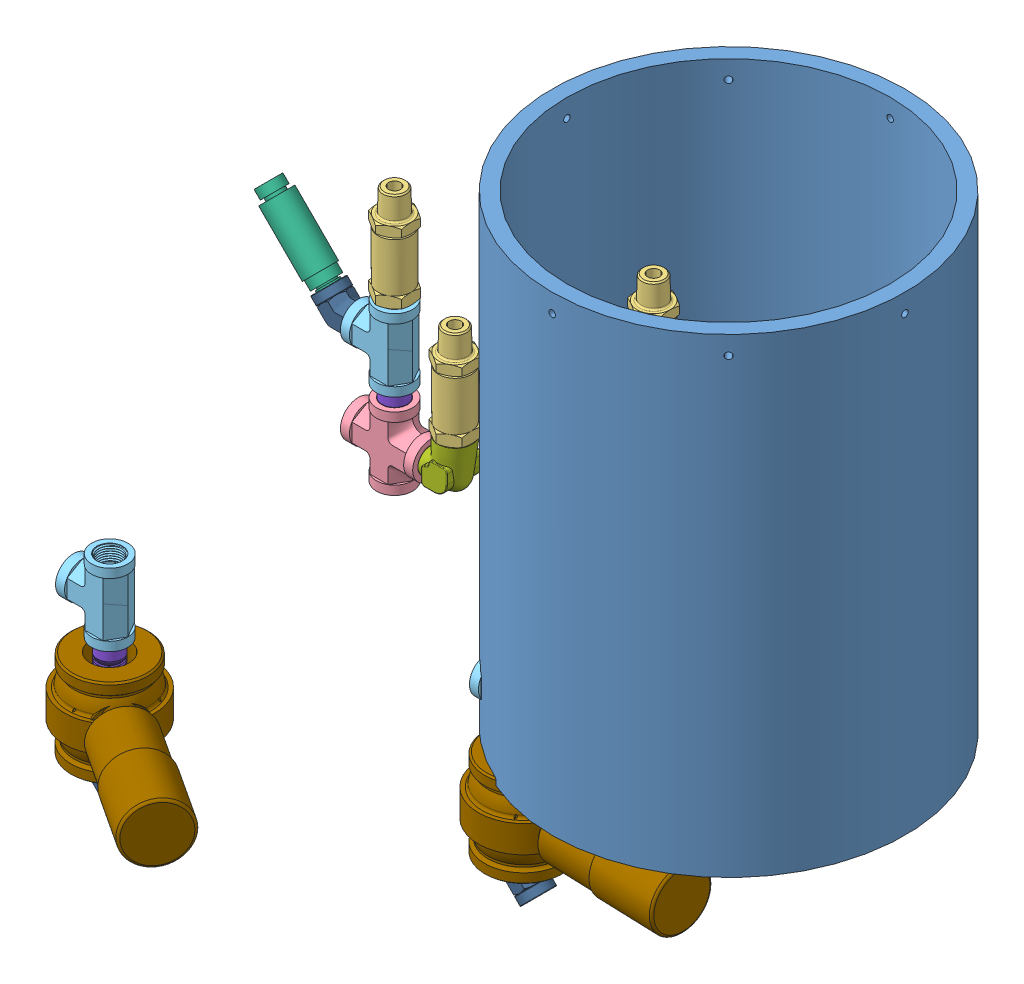
SolidWorks assembly FinCanAssembly, configuration Default. Lengths in mm.
Overall size (594.72 511.85 548.05).
27 component instances, 10 part files, 43 mates.
Components (placement in the parent):
- 000070-R03_FIN_CAN_AF-1: 000070-R03_FIN_CAN_AF [Default] at (23.1188 -196.0045 -17.088) size (304.8 406.4 304.8)
- launch_rail_lugs-1: launch_rail_lugs [Default] at (-92.4476 -84.8795 -132.6545) x (-0.707107 0 0.707107) z (-0.707107 0 -0.707107) size (76.2 32.2 34.22)
- TIN20021-1: TIN20021 [Default] at (7.6331 145.2519 32.2173) x (0 -1 0) z (0 0 1) size (102.11 28.58 33)
- TIN20021-2: TIN20021 [Default] at (-301.1748 13.7827 -52.7696) x (0 -1 0) z (0 0 1) size (102.11 28.58 33)
- 51205K175_EXTREME-PRESSURE 316 SS THREADED PIPE FITTING-1: 51205K175_EXTREME-PRESSURE 316 SS THREADED PIPE FITTING [51205K175] at (7.6331 -24.0899 32.2173) size (63.86 63.86 31.16)
- 51205K175_EXTREME-PRESSURE 316 SS THREADED PIPE FITTING-2: 51205K175_EXTREME-PRESSURE 316 SS THREADED PIPE FITTING [51205K175] at (-301.1748 -155.5591 -52.7696) x (0 -1 0) z (0 0 1) size (63.86 63.86 31.16)
- TIN20021-3: TIN20021 [Default] at (-248.9047 -63.8175 -52.7696) x (0 -1 0) z (0 0 1) size (102.11 28.58 33)
- TIN20021-6: TIN20021 [Default] at (59.9031 67.6517 32.2173) x (0 -1 0) z (0 0 1) size (102.11 28.58 33)
- 51205K245_EXTREME-PRESSURE 316 SS THREADED PIPE FITTING-1: 51205K245_EXTREME-PRESSURE 316 SS THREADED PIPE FITTING [51205K245] at (-301.1748 -81.9753 -52.7696) x (0 1 0) z (0 0 1) size (63.86 47.51 31.16)
- cryo-pducer-temp-1: cryo-pducer-temp [Default] at (-350.8641 -76.2279 -52.7696) x (0.707107 0.707107 0) z (0 0 1) size (25.65 83.82 25.65)
- 51205K245_EXTREME-PRESSURE 316 SS THREADED PIPE FITTING-2: 51205K245_EXTREME-PRESSURE 316 SS THREADED PIPE FITTING [51205K245] at (7.6331 49.4939 32.2173) x (0 1 0) z (0 0 1) size (63.86 47.51 31.16)
- cryo-pducer-temp-2: cryo-pducer-temp [Default] at (-13.4489 49.4939 32.2173) x (0 1 0) z (0 0 1) size (25.65 83.82 25.65)
- 3861T240_MED-PRESSURE ANODIZED ALUM THRD PIPE FITTING-1: 3861T240_MED-PRESSURE ANODIZED ALUM THRD PIPE FITTING [3861T24] at (-248.9047 -125.7935 -52.7696) x (0 0 -1) z (0 1 0) size (30.97 56.51 41.63)
- 44665K173_STANDARD-WALL ALUMINUM THREADED PIPE NIPPLE-1: 44665K173_STANDARD-WALL ALUMINUM THREADED PIPE NIPPLE [44665K173] at (-301.1748 -118.7672 -52.7696) x (1 0 0) z (0 -1 0) size (22.19 22.36 51.97)
- 44665K173_STANDARD-WALL ALUMINUM THREADED PIPE NIPPLE-2: 44665K173_STANDARD-WALL ALUMINUM THREADED PIPE NIPPLE [44665K173] at (7.6331 12.702 32.2173) x (1 0 0) z (0 -1 0) size (22.19 22.36 51.97)
- 3861T240_MED-PRESSURE ANODIZED ALUM THRD PIPE FITTING-2: 3861T240_MED-PRESSURE ANODIZED ALUM THRD PIPE FITTING [3861T24] at (59.9031 5.6757 32.2173) x (0 0 -1) z (0 1 0) size (30.97 56.51 41.63)
- atomatik-1: atomatik [Default] at (58.6758 -183.8479 -36.0375) size (76.23 180.98 78)
- atomatik-2: atomatik [Default] at (-229.8589 -151.0153 264.6801) x (0 -1 0) z (-0.546944 0 0.837169) size (76.23 180.98 78)
- atomatik-3: atomatik [Default] at (-46.8177 -221.3586 90.098) x (0 -1 0) z (-0.035722 0 0.999362) size (76.23 180.98 78)
- atomatik-4: atomatik [Default] at (57.6992 -182.5795 58.8478) size (76.23 180.98 78)
- 51205K245_EXTREME-PRESSURE 316 SS THREADED PIPE FITTING-3: 51205K245_EXTREME-PRESSURE 316 SS THREADED PIPE FITTING [51205K245] at (-46.8177 -148.3929 90.098) x (0 1 0) z (0 0 1) size (63.86 47.51 31.16)
- 44665K173_STANDARD-WALL ALUMINUM THREADED PIPE NIPPLE-3: 44665K173_STANDARD-WALL ALUMINUM THREADED PIPE NIPPLE [44665K173] at (-46.8177 -185.1848 90.098) x (1 0 0) z (0 -1 0) size (22.19 22.36 51.97)
- 51205K245_EXTREME-PRESSURE 316 SS THREADED PIPE FITTING-4: 51205K245_EXTREME-PRESSURE 316 SS THREADED PIPE FITTING [51205K245] at (-229.8589 -78.0496 264.6801) x (0 1 0) z (0 0 1) size (63.86 47.51 31.16)
- 44665K173_STANDARD-WALL ALUMINUM THREADED PIPE NIPPLE-4: 44665K173_STANDARD-WALL ALUMINUM THREADED PIPE NIPPLE [44665K173] at (-229.8589 -114.8415 264.6801) x (1 0 0) z (0 -1 0) size (22.19 22.36 51.97)
- 48805K184_PRECISION EXTREME-PRESSURE 316SS PIPE FITTING-1: 48805K184_PRECISION EXTREME-PRESSURE 316SS PIPE FITTING [48805K184] at (-46.8177 -279.661 90.098) x (0 -1 0) z (0 0 1) size (48.72 34.63 25.66)
- 48805K184_PRECISION EXTREME-PRESSURE 316SS PIPE FITTING-2: 48805K184_PRECISION EXTREME-PRESSURE 316SS PIPE FITTING [48805K184] at (-229.8589 -209.3177 264.6801) x (0 -1 0) z (0 0 1) size (48.72 34.63 25.66)
- 48805K184_PRECISION EXTREME-PRESSURE 316SS PIPE FITTING-3: 48805K184_PRECISION EXTREME-PRESSURE 316SS PIPE FITTING [48805K184] at (-345.1168 -81.9753 -52.7696) x (-1 0 0) z (0 0 -1) size (48.72 34.63 25.66)
Mates (geometry in assembly coordinates):
- Concentric1: concentric aligned: cylinder of 000070-R03_FIN_CAN_AF-1 through (23.1188 210.3955 -17.088) axis (0 -1 0) radius 152.4; cylinder of launch_rail_lugs-1 through (23.1188 -53.1295 -17.088) axis (0 -1 0) radius 152.4
- Concentric2: concentric aligned: cylinder of 000070-R03_FIN_CAN_AF-1 through (-90.7059 -69.0045 -118.7894) axis (-0.707107 0 -0.707107) radius 1.7272; cylinder of launch_rail_lugs-1 through (-98.5093 -69.0045 -126.5928) axis (-0.707107 0 -0.707107) radius 2.4574
- Distance8: distance = 2.54 mm anti-aligned: plane of 51205K245_EXTREME-PRESSURE 316 SS THREADED PIPE FITTING-1 through (-301.1748 -50.7333 -52.7696) normal (0 1 0); plane of TIN20021-2 through (-301.1748 -48.1933 -61.0184) normal (0 -1 0)
- Concentric19: concentric aligned: cone of TIN20021-1 through (7.6331 81.8471 32.2173) axis (0 -1 0); cylinder of 51205K245_EXTREME-PRESSURE 316 SS THREADED PIPE FITTING-2 through (7.6331 67.2739 32.2173) axis (0 -1 0) radius 8.001
- Distance11: distance = 2.54 mm anti-aligned: plane of TIN20021-1 through (7.6331 83.2759 23.9684) normal (0 -1 0); plane of 51205K245_EXTREME-PRESSURE 316 SS THREADED PIPE FITTING-2 through (7.6331 80.7359 32.2173) normal (0 1 0)
- Concentric21: concentric aligned: cylinder of 51205K245_EXTREME-PRESSURE 316 SS THREADED PIPE FITTING-2 through (-10.1469 49.4939 32.2173) axis (1 0 0) radius 8.001; cylinder of cryo-pducer-temp-2 through (-13.4489 49.4939 32.2173) axis (1 0 0) radius 8.89
- Distance12: distance = 2.54 mm anti-aligned: plane of cryo-pducer-temp-2 through (-26.1489 60.9239 32.2173) normal (1 0 0); plane of 51205K245_EXTREME-PRESSURE 316 SS THREADED PIPE FITTING-2 through (-23.6089 49.4939 32.2173) normal (-1 0 0)
- Concentric22: concentric anti-aligned: cylinder of 51205K175_EXTREME-PRESSURE 316 SS THREADED PIPE FITTING-2 through (-301.1748 -173.3391 -52.7696) axis (0 1 0) radius 8.001; cylinder of 44665K173_STANDARD-WALL ALUMINUM THREADED PIPE NIPPLE-1 through (-301.1748 -92.78 -52.7696) axis (0 -1 0) radius 7.8994
- Coincident14: coincident aligned: plane of 51205K175_EXTREME-PRESSURE 316 SS THREADED PIPE FITTING-2 through (-301.1748 -124.3171 -52.7696) normal (0 1 0); circle of 44665K173_STANDARD-WALL ALUMINUM THREADED PIPE NIPPLE-1
- Concentric23: concentric anti-aligned: cylinder of 51205K245_EXTREME-PRESSURE 316 SS THREADED PIPE FITTING-1 through (-301.1748 -113.2173 -52.7696) axis (0 1 0) radius 15.5812; cylinder of 44665K173_STANDARD-WALL ALUMINUM THREADED PIPE NIPPLE-1 through (-301.1748 -113.2173 -52.7696) axis (0 -1 0) radius 10.668
- Coincident15: coincident aligned: plane of 51205K245_EXTREME-PRESSURE 316 SS THREADED PIPE FITTING-1 through (-301.1748 -113.2173 -52.7696) normal (0 -1 0); circle of 44665K173_STANDARD-WALL ALUMINUM THREADED PIPE NIPPLE-1
- Concentric25: concentric aligned: cylinder of 51205K175_EXTREME-PRESSURE 316 SS THREADED PIPE FITTING-1 through (7.6331 7.1521 32.2173) axis (0 -1 0) radius 15.5812; cylinder of 44665K173_STANDARD-WALL ALUMINUM THREADED PIPE NIPPLE-2 through (7.6331 18.2519 32.2173) axis (0 -1 0) radius 10.668
- Coincident16: coincident aligned: plane of 51205K175_EXTREME-PRESSURE 316 SS THREADED PIPE FITTING-1 through (7.6331 7.1521 32.2173) normal (0 1 0); circle of 44665K173_STANDARD-WALL ALUMINUM THREADED PIPE NIPPLE-2
- Concentric26: concentric aligned: cylinder of 51205K245_EXTREME-PRESSURE 316 SS THREADED PIPE FITTING-2 through (7.6331 67.2739 32.2173) axis (0 -1 0) radius 8.001; cylinder of 44665K173_STANDARD-WALL ALUMINUM THREADED PIPE NIPPLE-2 through (7.6331 18.2519 32.2173) axis (0 -1 0) radius 10.668
- Coincident17: coincident aligned: plane of 51205K245_EXTREME-PRESSURE 316 SS THREADED PIPE FITTING-2 through (7.6331 18.2519 32.2173) normal (0 -1 0); circle of 44665K173_STANDARD-WALL ALUMINUM THREADED PIPE NIPPLE-2
- Concentric27: concentric aligned: cylinder of 51205K175_EXTREME-PRESSURE 316 SS THREADED PIPE FITTING-2 through (-283.3948 -155.5591 -52.7696) axis (-1 0 0) radius 8.001; cylinder of 3861T240_MED-PRESSURE ANODIZED ALUM THRD PIPE FITTING-1 through (-266.7641 -155.5591 -52.7696) axis (-1 0 0) radius 6.7469
- Coincident18: coincident anti-aligned: plane of 51205K175_EXTREME-PRESSURE 316 SS THREADED PIPE FITTING-2 through (-269.9328 -155.5591 -52.7696) normal (1 0 0); plane of 3861T240_MED-PRESSURE ANODIZED ALUM THRD PIPE FITTING-1 through (-269.9328 -173.4185 -37.6883) normal (-1 0 0)
- Concentric28: concentric aligned: cone of TIN20021-2 through (-301.1748 -49.622 -52.7696) axis (0 -1 0); cylinder of 51205K245_EXTREME-PRESSURE 316 SS THREADED PIPE FITTING-1 through (-301.1748 -64.1953 -52.7696) axis (0 -1 0) radius 8.001
- Concentric29: concentric aligned: cylinder of 3861T240_MED-PRESSURE ANODIZED ALUM THRD PIPE FITTING-2 through (42.0438 -24.0899 32.2173) axis (-1 0 0) radius 6.7469; cylinder of 51205K175_EXTREME-PRESSURE 316 SS THREADED PIPE FITTING-1 through (25.4131 -24.0899 32.2173) axis (-1 0 0) radius 8.001
- Coincident19: coincident anti-aligned: plane of 51205K175_EXTREME-PRESSURE 316 SS THREADED PIPE FITTING-1 through (38.8751 -24.0899 32.2173) normal (1 0 0); plane of 3861T240_MED-PRESSURE ANODIZED ALUM THRD PIPE FITTING-2 through (38.8751 -41.9493 47.2985) normal (-1 0 0)
- Parallel1: parallel aligned: plane of 51205K175_EXTREME-PRESSURE 316 SS THREADED PIPE FITTING-1 through (19.3489 -35.8057 18.7235) normal (0 0 -1); plane of 3861T240_MED-PRESSURE ANODIZED ALUM THRD PIPE FITTING-2 through (56.7281 -20.9149 17.136) normal (0 0 -1)
- Parallel2: parallel aligned: plane of 51205K175_EXTREME-PRESSURE 316 SS THREADED PIPE FITTING-2 through (-312.8905 -167.2748 -66.2633) normal (0 0 -1); plane of 3861T240_MED-PRESSURE ANODIZED ALUM THRD PIPE FITTING-1 through (-252.0797 -152.3841 -67.8508) normal (0 0 -1)
- Concentric30: concentric aligned: cone of TIN20021-3 through (-248.9047 -127.2222 -52.7696) axis (0 -1 0); circle of 3861T240_MED-PRESSURE ANODIZED ALUM THRD PIPE FITTING-1
- Coincident23: coincident anti-aligned: plane of TIN20021-3 through (-248.9047 -125.7935 -61.0184) normal (0 -1 0); plane of 3861T240_MED-PRESSURE ANODIZED ALUM THRD PIPE FITTING-1 through (-248.9047 -125.7935 -52.7696) normal (0 1 0)
- Concentric31: concentric aligned: cone of TIN20021-6 through (59.9031 4.2469 32.2173) axis (0 -1 0); circle of 3861T240_MED-PRESSURE ANODIZED ALUM THRD PIPE FITTING-2
- Coincident25: coincident anti-aligned: plane of TIN20021-6 through (59.9031 5.6757 23.9684) normal (0 -1 0); plane of 3861T240_MED-PRESSURE ANODIZED ALUM THRD PIPE FITTING-2 through (59.9031 5.6757 32.2173) normal (0 1 0)
- Concentric32: concentric anti-aligned: cylinder of 51205K245_EXTREME-PRESSURE 316 SS THREADED PIPE FITTING-3 through (-46.8177 -179.6349 90.098) axis (0 1 0) radius 15.5812; cylinder of 44665K173_STANDARD-WALL ALUMINUM THREADED PIPE NIPPLE-3 through (-46.8177 -179.6349 90.098) axis (0 -1 0) radius 10.668
- Concentric33: concentric anti-aligned: cylinder of 51205K245_EXTREME-PRESSURE 316 SS THREADED PIPE FITTING-4 through (-229.8589 -109.2916 264.6801) axis (0 1 0) radius 15.5812; cylinder of 44665K173_STANDARD-WALL ALUMINUM THREADED PIPE NIPPLE-4 through (-229.8589 -109.2916 264.6801) axis (0 -1 0) radius 10.668
- Coincident26: coincident aligned: plane of 51205K245_EXTREME-PRESSURE 316 SS THREADED PIPE FITTING-3 through (-46.8177 -179.6349 90.098) normal (0 -1 0); circle of 44665K173_STANDARD-WALL ALUMINUM THREADED PIPE NIPPLE-3
- Coincident27: coincident aligned: plane of 51205K245_EXTREME-PRESSURE 316 SS THREADED PIPE FITTING-4 through (-229.8589 -109.2916 264.6801) normal (0 -1 0); circle of 44665K173_STANDARD-WALL ALUMINUM THREADED PIPE NIPPLE-4
- Concentric34: concentric anti-aligned: cylinder of atomatik-3 through (-46.8177 -245.9894 90.098) axis (0 1 0) radius 16.775; cylinder of 44665K173_STANDARD-WALL ALUMINUM THREADED PIPE NIPPLE-3 through (-46.8177 -179.6349 90.098) axis (0 -1 0) radius 10.668
- Coincident28: coincident aligned: plane of atomatik-3 through (-63.582 -190.7347 89.4988) normal (0 1 0); circle of 44665K173_STANDARD-WALL ALUMINUM THREADED PIPE NIPPLE-3
- Coincident29: coincident aligned: plane of atomatik-2 through (-243.9024 -120.3914 255.5051) normal (0 1 0); circle of 44665K173_STANDARD-WALL ALUMINUM THREADED PIPE NIPPLE-4
- Concentric35: concentric anti-aligned: cylinder of atomatik-2 through (-229.8589 -175.6461 264.6801) axis (0 1 0) radius 16.775; cylinder of 44665K173_STANDARD-WALL ALUMINUM THREADED PIPE NIPPLE-4 through (-229.8589 -109.2916 264.6801) axis (0 -1 0) radius 10.668
- Concentric36: concentric aligned: cylinder of atomatik-2 through (-229.8589 -175.6461 264.6801) axis (0 1 0) radius 16.775; cylinder of 48805K184_PRECISION EXTREME-PRESSURE 316SS PIPE FITTING-2 through (-229.8589 -209.3177 264.6801) axis (0 1 0) radius 5.207
- Concentric38: concentric aligned: cylinder of atomatik-3 through (-46.8177 -245.9894 90.098) axis (0 1 0) radius 16.775; cylinder of 48805K184_PRECISION EXTREME-PRESSURE 316SS PIPE FITTING-1 through (-46.8177 -279.661 90.098) axis (0 1 0) radius 5.207
- Coincident30: coincident anti-aligned: plane of atomatik-3 through (-69.9279 -266.961 89.2719) normal (0 -1 0); plane of 48805K184_PRECISION EXTREME-PRESSURE 316SS PIPE FITTING-1 through (-46.8177 -266.961 112.323) normal (0 1 0)
- Coincident31: coincident anti-aligned: plane of atomatik-2 through (-249.2184 -196.6177 252.032) normal (0 -1 0); plane of 48805K184_PRECISION EXTREME-PRESSURE 316SS PIPE FITTING-2 through (-229.8589 -196.6177 286.9051) normal (0 1 0)
- Concentric39: concentric aligned: cylinder of 51205K245_EXTREME-PRESSURE 316 SS THREADED PIPE FITTING-1 through (-318.9548 -81.9753 -52.7696) axis (1 0 0) radius 8.001; cylinder of 48805K184_PRECISION EXTREME-PRESSURE 316SS PIPE FITTING-3 through (-345.1168 -81.9753 -52.7696) axis (1 0 0) radius 5.207
- Coincident32: coincident anti-aligned: plane of 51205K245_EXTREME-PRESSURE 316 SS THREADED PIPE FITTING-1 through (-332.4168 -81.9753 -52.7696) normal (-1 0 0); plane of 48805K184_PRECISION EXTREME-PRESSURE 316SS PIPE FITTING-3 through (-332.4168 -81.9753 -74.9946) normal (1 0 0)
- Concentric40: concentric aligned: cylinder of cryo-pducer-temp-1 through (-350.8641 -76.2279 -52.7696) axis (0.707107 -0.707107 0) radius 8.89; cone of 48805K184_PRECISION EXTREME-PRESSURE 316SS PIPE FITTING-3 through (-350.724 -76.368 -52.7696) axis (0.707107 -0.707107 0)
- Distance13: distance = 2.54 mm anti-aligned: plane of cryo-pducer-temp-1 through (-351.7622 -59.1654 -52.7696) normal (0.707107 -0.707107 0); plane of 48805K184_PRECISION EXTREME-PRESSURE 316SS PIPE FITTING-3 through (-358.0483 -69.0437 -52.7696) normal (-0.707107 0.707107 0)
- Parallel3: parallel aligned: plane of 51205K245_EXTREME-PRESSURE 316 SS THREADED PIPE FITTING-1 through (-301.1748 -81.9753 -39.2758) normal (0 0 1); plane of 48805K184_PRECISION EXTREME-PRESSURE 316SS PIPE FITTING-3 through (-345.1168 -81.9753 -41.6571) normal (0 0 1)
